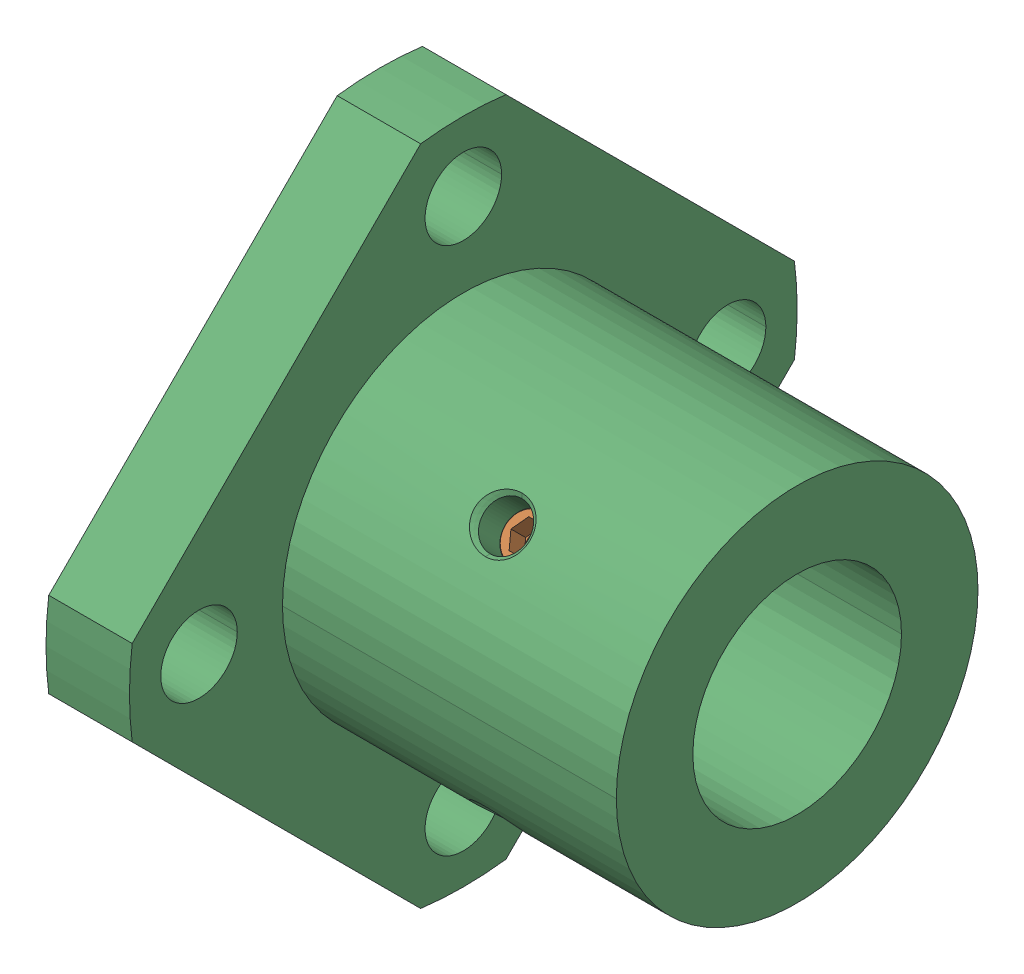
SolidWorks assembly SSTHSN15_MB, configuration Default. Lengths in mm.
Overall size (30 48 48).
3 component instances, 2 part files, 0 mates.
Components (placement in the parent):
- SSTHSN15_MB_3-1: SSTHSN15_MB_3 [Default] at (18 -5.3033 5.3033) x (0 0.707107 -0.707107) z (-1 0 0) size (3 4 4)
- SSTHSN15_MB_3-2: SSTHSN15_MB_3 [Default] at (18 5.3033 5.3033) x (0 -0.707107 -0.707107) z (-1 0 0) size (3 4 4)
- SSTHSN15_MB_6-1: SSTHSN15_MB_6 [Default] at origin size (30 48 48)
